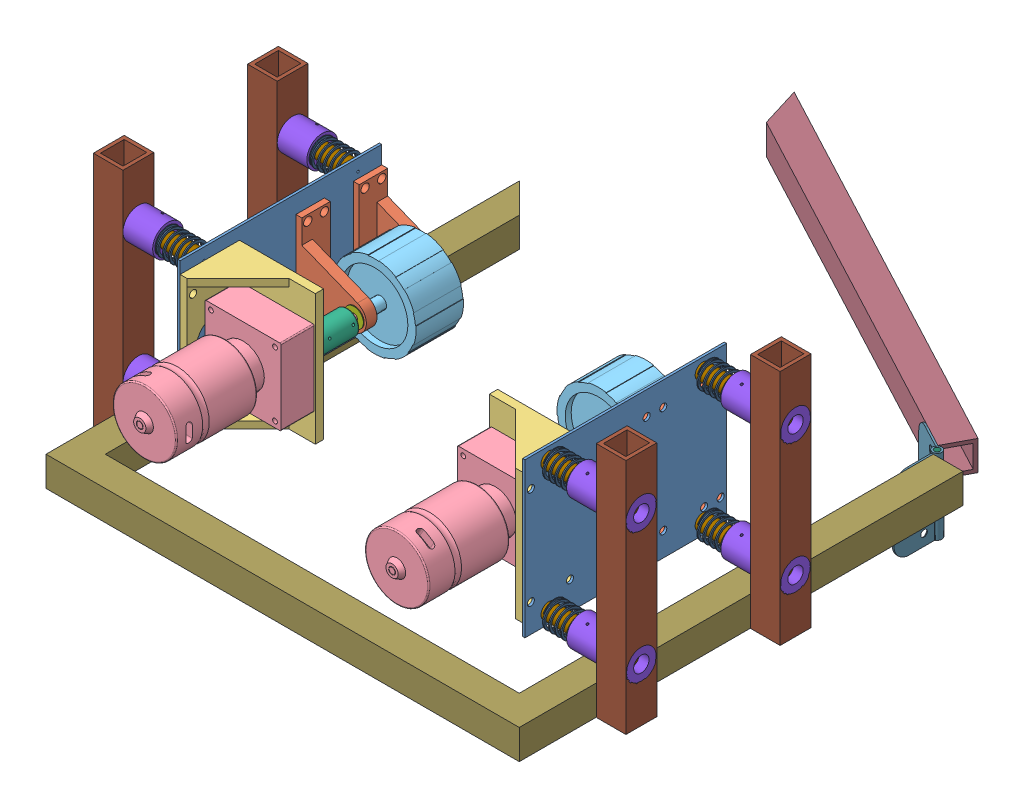
SolidWorks assembly final pole climbe, configuration Default. Lengths in mm.
Overall size (449 238.36 593.87).
65 component instances, 15 part files, 4 mates.
Components (placement in the parent):
- pole climb part 1 with suspension-1: pole climb part 1 with suspension [Default] at (-124.3182 262.0483 624.2536) x (0 0 1) z (0 1 0) size (243.51 172.32 200)
  - pole clib part 1-1: pole clib part 1 [Default] at (50.8325 146.9864 142.7782) size (242.35 94.18 130)
    - base-1: base [Default] at (31.7698 -36.7623 7.5319) size (170 2 130)
    - part2v2-1: part2v2 [Default] at (-41.2302 -34.7623 7.5319) x (0 0 1) z (-1 0 0) size (100 59.4 24)
    - part2v2-2: part2v2 [Default] at (7.1483 -34.7623 7.5319) x (0 0 -1) z (1 0 0) size (100 59.4 24)
    - motor holder-1: motor holder [Default] at (91.7698 -34.7623 7.5316) x (0 0 1) z (-1 0 0) size (110 71 50)
    - motor-1: motor [Default] at (73.7698 3.2377 7.5316) x (0 0 1) z (0 1 0) size (64 240 64)
    - wheel-1: wheel [Default] at (-37.2381 15.2377 7.5316) x (0 -0.971221 -0.238181) z (0 -0.238181 0.971221) size (69.84 50 70)
    - coupler-1: coupler [Default] at (65.5971 15.2377 7.5316) x (0 0.42254 -0.906344) z (0 0.906344 0.42254) size (20 40 20)
    - bearing-1: bearing [Default] at (-53.577 14.8159 7.5319) x (0 -0.990765 0.135587) z (0 0.135587 0.990765) size (16 10 16)
    - bearing-2: bearing [Default] at (19.7953 14.8159 7.5319) x (0 0.970411 -0.241458) z (0 0.241458 0.970411) size (16 10 16)
  - suspension-1: suspension [Default] at (2.0051 67.4489 205.579) x (-0.911089 0 -0.41221) z (0.41221 0 -0.911089) size (32.71 78.15 32.71)
    - suspension 1-1: suspension 1 [Default] at (-14.0996 -35.3728 6.6744) size (26 50 26)
    - suspension 2-1: suspension 2 [Default] at (-14.0996 -27.2249 6.6744) x (0.4026 0 -0.915376) z (0.915376 0 0.4026) size (13 70 13)
    - spring-1: spring [Default] at (-14.0665 37.5022 7.0045) x (0.773571 0 0.63371) z (0 -1 0) size (23.25 23.23 23.91)
  - suspension-2: suspension [Default] at (2.0051 67.4489 95.579) x (-0.911089 0 -0.41221) z (0.41221 0 -0.911089) size (32.71 78.15 32.71)
    - suspension 1-1: suspension 1 [Default] at (-14.0996 -35.3728 6.6744) size (26 50 26)
    - suspension 2-1: suspension 2 [Default] at (-14.0996 -27.2249 6.6744) x (0.4026 0 -0.915376) z (0.915376 0 0.4026) size (13 70 13)
    - spring-1: spring [Default] at (-14.0665 37.5022 7.0045) x (0.773571 0 0.63371) z (0 -1 0) size (23.25 23.23 23.91)
  - suspension-3: suspension [Default] at (132.0051 67.4489 205.579) x (-0.911089 0 -0.41221) z (0.41221 0 -0.911089) size (32.71 78.15 32.71)
    - suspension 1-1: suspension 1 [Default] at (-14.0996 -35.3728 6.6744) size (26 50 26)
    - suspension 2-1: suspension 2 [Default] at (-14.0996 -27.2249 6.6744) x (0.4026 0 -0.915376) z (0.915376 0 0.4026) size (13 70 13)
    - spring-1: spring [Default] at (-14.0665 37.5022 7.0045) x (0.773571 0 0.63371) z (0 -1 0) size (23.25 23.23 23.91)
  - suspension-4: suspension [Default] at (132.0051 67.4489 95.579) x (-0.911089 0 -0.41221) z (0.41221 0 -0.911089) size (32.71 78.15 32.71)
    - suspension 1-1: suspension 1 [Default] at (-14.0996 -35.3728 6.6744) size (26 50 26)
    - suspension 2-1: suspension 2 [Default] at (-14.0996 -27.2249 6.6744) x (0.4026 0 -0.915376) z (0.915376 0 0.4026) size (13 70 13)
    - spring-1: spring [Default] at (-14.0665 37.5022 7.0045) x (0.773571 0 0.63371) z (0 -1 0) size (23.25 23.23 23.91)
  - joint-1: joint [Default] at (17.6023 32.0761 150.3101) x (0 0 -1) z (1 0 0) size (200 25 26)
  - joint-2: joint [Default] at (147.6023 32.0761 150.3101) x (0 0 -1) z (1 0 0) size (200 25 26)
- frame-1: frame [Default] at (9.4236 149.744 307.8301) size (399 63.5 579.78)
  - u-part1-1: u-part1 [Default] at (122.8343 162.7552 342.436) size (399 25 399)
  - u-part2-1: u-part2 [Default] at (58.8326 162.7552 228.4274) x (0.88327 0 0.468865) z (-0.468865 0 0.88327) size (374 25 25)
  - Hinge_01-2: Hinge_01 [Default] at (295.8103 124.2552 201.0221) x (0 0 1) z (0 -1 0) size (59.41 40.75 63.5)
    - Hinge_01-1: Hinge_01 [Default] at origin size (42 7.8 63.5)
    - Hinge_01-2: Hinge_01 [Default] at (-56.0759 33.72 -63.5) x (-0.468865 0.88327 0) z (0 0 -1) size (42 7.8 63.5)
    - Hinge_01_Pin-1: Hinge_01_Pin [Default] at (-56.0759 33.72 -63.5) x (-0.468865 0.88327 0) z (0 0 -1) size (4.75 4.75 63.5)
- pole climb part 1 with suspension-2: pole climb part 1 with suspension [Default] at (388.834 562.6657 624.2536) x (0 0 1) z (0 -1 0) size (243.51 172.32 200)
  - pole clib part 1-1: pole clib part 1 [Default] at (50.8325 146.9864 142.7782) size (242.35 94.18 130)
    - base-1: base [Default] at (31.7698 -36.7623 7.5319) size (170 2 130)
    - part2v2-1: part2v2 [Default] at (-41.2302 -34.7623 7.5319) x (0 0 1) z (-1 0 0) size (100 59.4 24)
    - part2v2-2: part2v2 [Default] at (7.1483 -34.7623 7.5319) x (0 0 -1) z (1 0 0) size (100 59.4 24)
    - motor holder-1: motor holder [Default] at (91.7698 -34.7623 7.5316) x (0 0 1) z (-1 0 0) size (110 71 50)
    - motor-1: motor [Default] at (73.7698 3.2377 7.5316) x (0 0 1) z (0 1 0) size (64 240 64)
    - wheel-1: wheel [Default] at (-37.2381 15.2377 7.5316) x (0 -0.971221 -0.238181) z (0 -0.238181 0.971221) size (69.84 50 70)
    - coupler-1: coupler [Default] at (65.5971 15.2377 7.5316) x (0 0.42254 -0.906344) z (0 0.906344 0.42254) size (20 40 20)
    - bearing-1: bearing [Default] at (-53.577 14.8159 7.5319) x (0 -0.990765 0.135587) z (0 0.135587 0.990765) size (16 10 16)
    - bearing-2: bearing [Default] at (19.7953 14.8159 7.5319) x (0 0.970411 -0.241458) z (0 0.241458 0.970411) size (16 10 16)
  - suspension-1: suspension [Default] at (2.0051 67.4489 205.579) x (-0.911089 0 -0.41221) z (0.41221 0 -0.911089) size (32.71 78.15 32.71)
    - suspension 1-1: suspension 1 [Default] at (-14.0996 -35.3728 6.6744) size (26 50 26)
    - suspension 2-1: suspension 2 [Default] at (-14.0996 -27.2249 6.6744) x (0.4026 0 -0.915376) z (0.915376 0 0.4026) size (13 70 13)
    - spring-1: spring [Default] at (-14.0665 37.5022 7.0045) x (0.773571 0 0.63371) z (0 -1 0) size (23.25 23.23 23.91)
  - suspension-2: suspension [Default] at (2.0051 67.4489 95.579) x (-0.911089 0 -0.41221) z (0.41221 0 -0.911089) size (32.71 78.15 32.71)
    - suspension 1-1: suspension 1 [Default] at (-14.0996 -35.3728 6.6744) size (26 50 26)
    - suspension 2-1: suspension 2 [Default] at (-14.0996 -27.2249 6.6744) x (0.4026 0 -0.915376) z (0.915376 0 0.4026) size (13 70 13)
    - spring-1: spring [Default] at (-14.0665 37.5022 7.0045) x (0.773571 0 0.63371) z (0 -1 0) size (23.25 23.23 23.91)
  - suspension-3: suspension [Default] at (132.0051 67.4489 205.579) x (-0.911089 0 -0.41221) z (0.41221 0 -0.911089) size (32.71 78.15 32.71)
    - suspension 1-1: suspension 1 [Default] at (-14.0996 -35.3728 6.6744) size (26 50 26)
    - suspension 2-1: suspension 2 [Default] at (-14.0996 -27.2249 6.6744) x (0.4026 0 -0.915376) z (0.915376 0 0.4026) size (13 70 13)
    - spring-1: spring [Default] at (-14.0665 37.5022 7.0045) x (0.773571 0 0.63371) z (0 -1 0) size (23.25 23.23 23.91)
  - suspension-4: suspension [Default] at (132.0051 67.4489 95.579) x (-0.911089 0 -0.41221) z (0.41221 0 -0.911089) size (32.71 78.15 32.71)
    - suspension 1-1: suspension 1 [Default] at (-14.0996 -35.3728 6.6744) size (26 50 26)
    - suspension 2-1: suspension 2 [Default] at (-14.0996 -27.2249 6.6744) x (0.4026 0 -0.915376) z (0.915376 0 0.4026) size (13 70 13)
    - spring-1: spring [Default] at (-14.0665 37.5022 7.0045) x (0.773571 0 0.63371) z (0 -1 0) size (23.25 23.23 23.91)
  - joint-1: joint [Default] at (17.6023 32.0761 150.3101) x (0 0 -1) z (1 0 0) size (200 25 26)
  - joint-2: joint [Default] at (147.6023 32.0761 150.3101) x (0 0 -1) z (1 0 0) size (200 25 26)
Mates (geometry in assembly coordinates):
- Perpendicular1: perpendicular: plane of frame-1/u-part1-1 through (132.2579 337.4992 650.2661) normal (0 1 0); plane of pole climb part 1 with suspension-2/joint-2 through (331.7579 412.3556 771.8558) normal (-1 0 0)
- Perpendicular3: perpendicular: plane of pole climb part 1 with suspension-1/joint-2 through (-67.2421 412.3584 771.8558) normal (1 0 0); plane of frame-1/u-part1-1 through (132.2579 337.4992 650.2661) normal (0 1 0)
- Perpendicular4: perpendicular: plane of pole climb part 1 with suspension-1/joint-1 through (-67.2421 412.3584 641.8558) normal (1 0 0); plane of frame-1/u-part1-1 through (132.2579 337.4992 650.2661) normal (0 1 0)
- Distance2: distance = 0 mm: line of pole climb part 1 with suspension-1/joint-2 through (-67.2421 512.3584 784.8558) axis (0 -1 0); line of frame-1/u-part1-1 through (-67.2421 337.4992 450.7661) axis (0 0 1)
